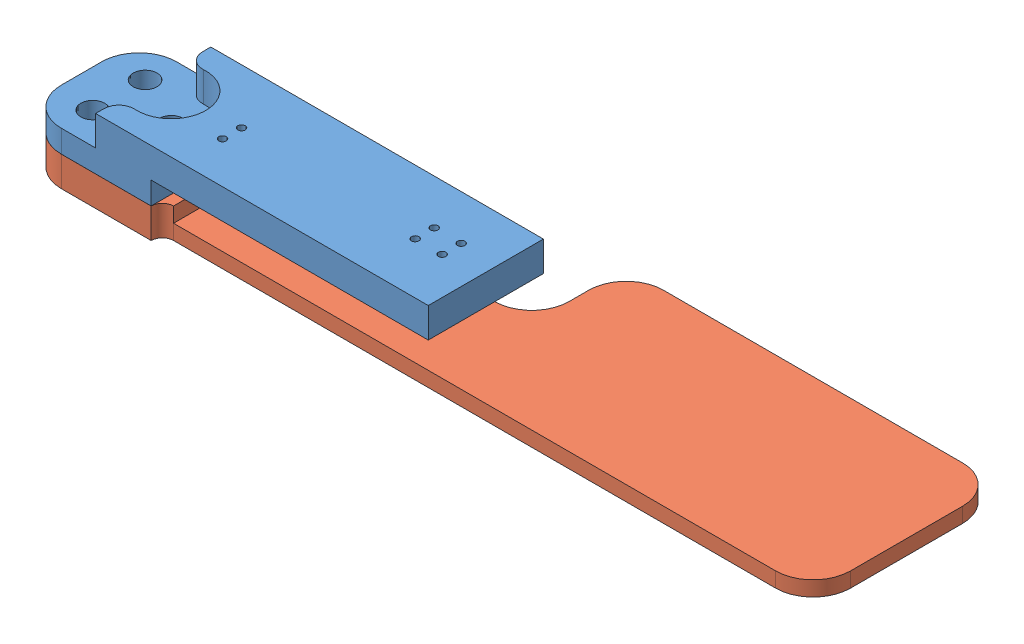
SolidWorks assembly 测试夹, configuration 默认. Lengths in mm.
Overall size (115.13 11 28.53).
2 component instances, 2 part files, 3 mates.
Components (placement in the parent):
- 测试针-1: 测试针 [默认] at (-107.0661 1.1509 201.64) size (115.13 7 27.84)
- 测试针_底-1: 测试针_底 [默认] at (-33.3045 -4.3491 125.5266) size (104 5.5 26.5)
Mates (geometry in assembly coordinates):
- 同心1: concentric anti-aligned: cylinder of 测试针-1 through (-28.3045 6.6509 122.8266) axis (0 -1 0) radius 1.6; cylinder of 测试针_底-1 through (-28.3045 -3.3491 122.8266) axis (0 1 0) radius 1.4
- 同心2: concentric anti-aligned: cylinder of 测试针-1 through (-21.3045 6.6509 119.3266) axis (0 -1 0) radius 1.6; cylinder of 测试针_底-1 through (-21.3045 -3.3491 119.3266) axis (0 1 0) radius 1.4
- 重合1: coincident anti-aligned: plane of 测试针-1 through (-107.0661 -0.3491 201.64) normal (0 -1 0); plane of 测试针_底-1 through (-33.3045 -0.3491 125.5266) normal (0 1 0)
